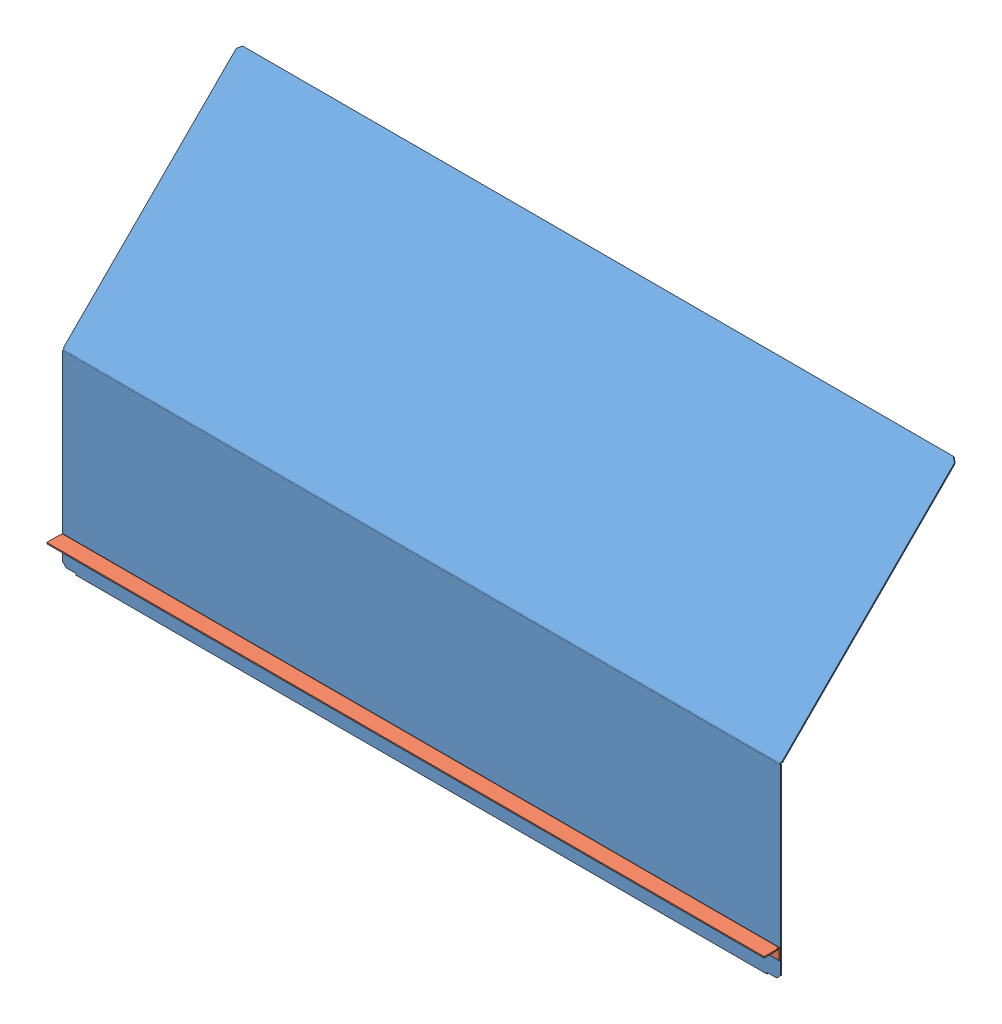
SolidWorks assembly 抽屜導板-1, configuration 預設. Lengths in mm.
Overall size (956 485.93 257.9).
2 component instances, 2 part files, 3 mates.
Components (placement in the parent):
- LB-A54A-02-27-1: LB-A54A-02-27 [預設] at (-79953.6583 17617.1683 116.5034) size (956 485.93 236.21)
- LB-A54-10-4-1: LB-A54-10-4 [預設] at (-85291.4913 17401.3144 118.1034) size (955 14.7 21.69)
Mates (geometry in assembly coordinates):
- 重合/共線/共點1: coincident: plane of LB-A54A-02-27-1 through (450.2689 -51.1565 118.1034) normal (0 0 1); plane of LB-A54-10-4-1 through (450.2689 -262.0104 118.1034) normal (0 0 -1)
- 重合/共線/共點2: coincident: plane of LB-A54A-02-27-1 through (450.2689 -52.1565 118.1034) normal (1 0 0); plane of LB-A54-10-4-1 through (450.2689 -276.7104 119.7034) normal (1 0 0)
- 重合/共線/共點3: coincident: line of LB-A54A-02-27-1 through (-505.7311 -262.0104 116.5034) axis (1 0 0); plane of LB-A54-10-4-1 through (450.2689 -262.0104 121.2954) normal (0 1 0)
